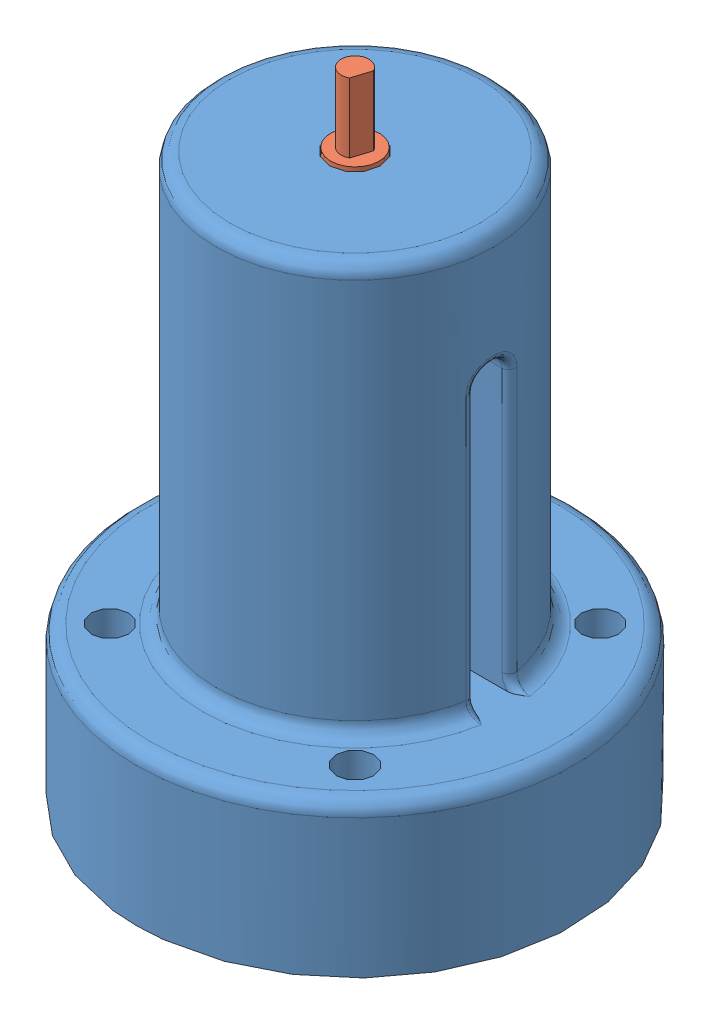
SolidWorks assembly full gripper, configuration По умолчанию. Lengths in mm.
Overall size (63 91.84 63).
3 component instances, 3 part files, 4 mates.
Components (placement in the parent):
- engine_gripper-1: engine_gripper [По умолчанию] at origin size (63 81 63)
- engine-1: engine [По умолчанию] at (0 26.85 0) x (0.953727 0 0.300675) z (-0.300675 0 0.953727) size (24.5 64.65 24.5)
- plug-1: plug [По умолчанию] x (0.670761 0 0.741674) z (-0.741674 0 0.670761) size (40.27 22.34 40)
Mates (geometry in assembly coordinates):
- Концентричный1: concentric anti-aligned: cylinder of engine_gripper-1 through (0 78.5 0) axis (0 1 0) radius 3.675; cylinder of engine-1 through (0 81.5 0) axis (0 -1 0) radius 3.5
- Совпадение1: coincident anti-aligned: plane of engine_gripper-1 through (0 78.5 0) normal (0 -1 0); plane of engine-1 through (0 78.5 0) normal (0 1 0)
- Концентричный3: concentric anti-aligned: circle of engine_gripper-1; circle of plug-1
- Совпадение4: coincident anti-aligned: plane of engine_gripper-1 through (0 20 0) normal (0 -1 0); plane of plug-1 through (0 20 0) normal (0 1 0)
